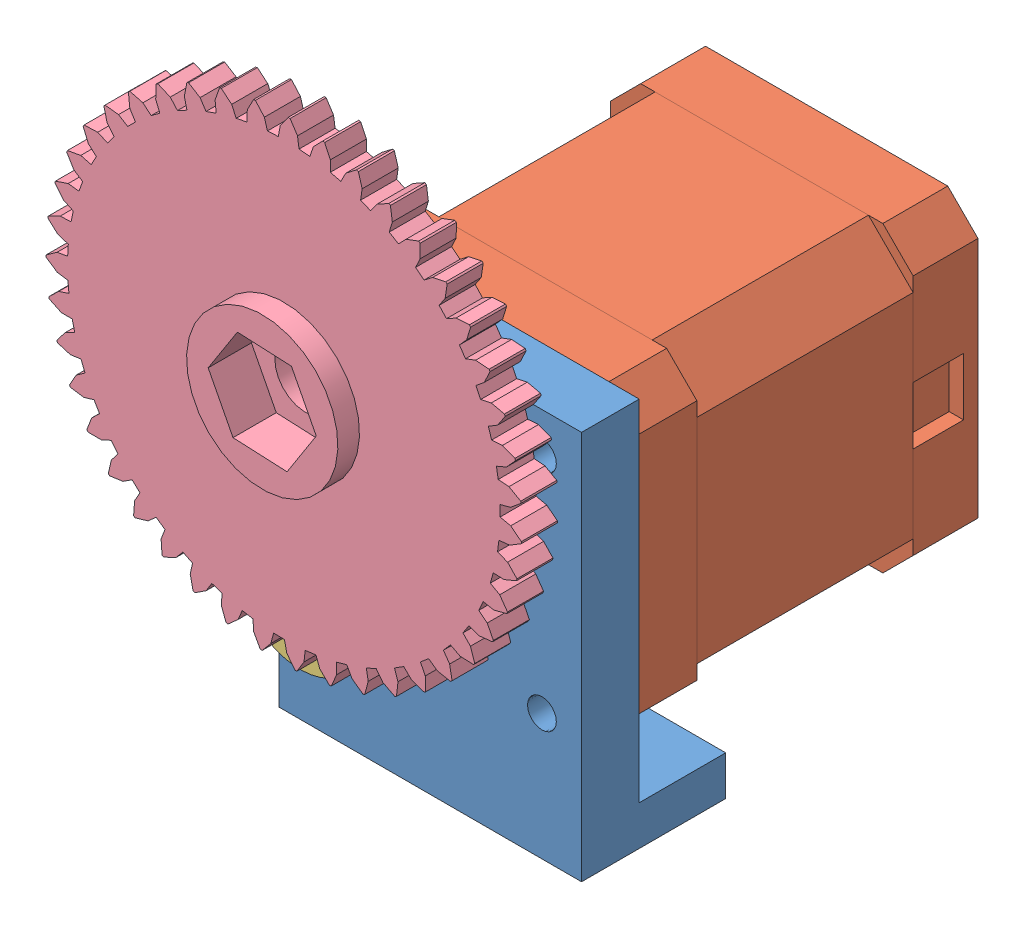
SolidWorks assembly extruder_bowden_ass, configuration Défaut. Lengths in mm.
Overall size (91.1 113.25 87.16).
4 component instances, 4 part files, 6 mates.
Components (placement in the parent):
- extruder_bowden-1: extruder_bowden [Défaut] at origin size (42 54 20)
- nema17-1: nema17 [Défaut] x (-1 0 0) z (0 0 -1) size (42 42 71)
- extruder_small_gear-1: extruder_small_gear [Défaut] at (0 0 26) x (0 0 -1) z (0.413198 -0.910641 0) size (18 18 18)
- extruder_big_gear-1: extruder_big_gear [Défaut] at (8.8594 34.6687 37.1636) x (0.539791 0.841799 0) z (0 0 -1) size (65.97 65.92 8)
Mates (geometry in assembly coordinates):
- Coaxiale1: concentric aligned: cylinder of extruder_bowden-1 through (0 0 8) axis (0 0 -1) radius 11.25; cylinder of nema17-1 through (0 0 2) axis (0 0 -1) radius 11
- Coaxiale2: concentric anti-aligned: cylinder of extruder_bowden-1 through (-15.5 15.5 8) axis (0 0 -1) radius 2; cylinder of nema17-1 through (-15.5 15.5 -5) axis (0 0 1) radius 1.5
- Coïncidente1: coincident anti-aligned: plane of extruder_bowden-1 through (0 0 0) normal (0 0 -1); plane of nema17-1 through (0 0 0) normal (0 0 1)
- Coaxiale3: concentric anti-aligned: cylinder of nema17-1 through (0 0 24) axis (0 0 -1) radius 2.5; cylinder of extruder_small_gear-1 through (0 0 8) axis (0 0 1) radius 2.65
- Coïncidente2: coincident anti-aligned: plane of extruder_bowden-1 through (0 0 8) normal (0 0 1); plane of extruder_small_gear-1 through (0 0 8) normal (0 0 -1)
- Parallèle1: parallel anti-aligned: plane of extruder_small_gear-1 through (0 0 26) normal (0 0 1); plane of extruder_big_gear-1 through (8.8594 34.6687 32.1636) normal (0 0 -1)
